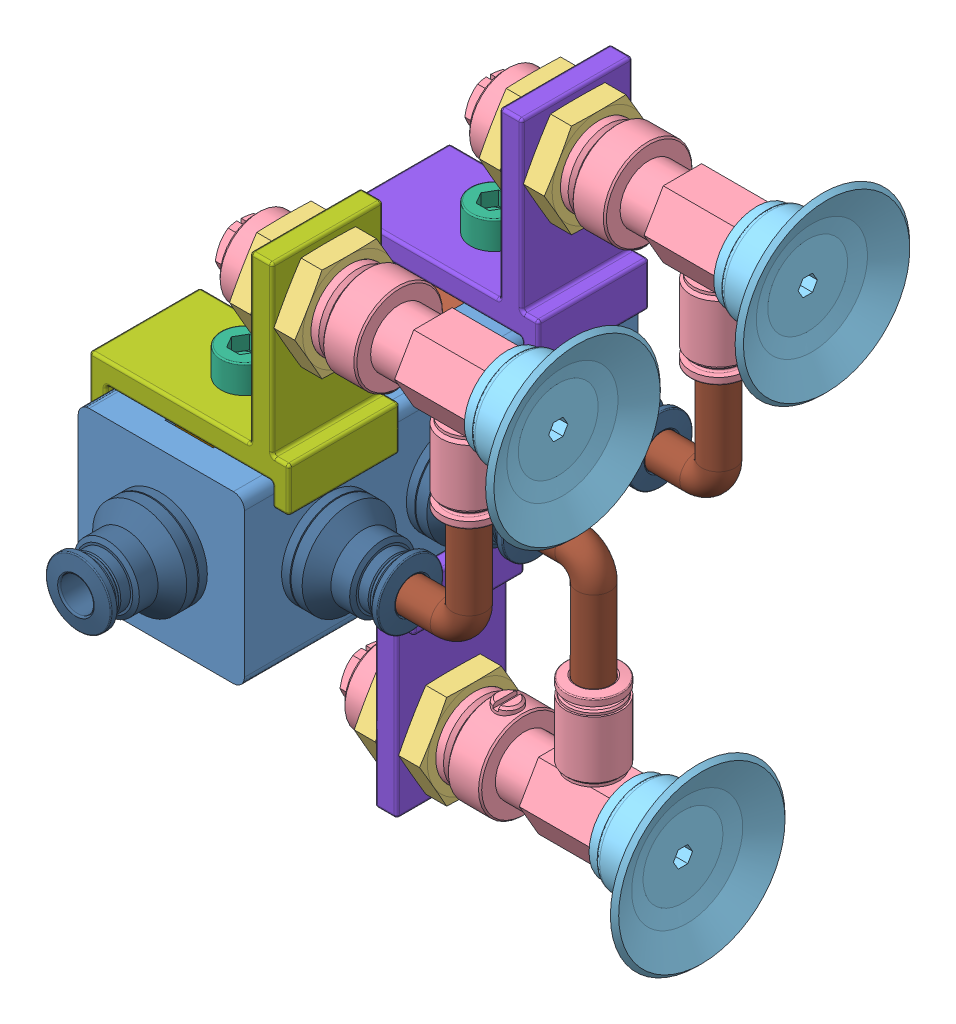
SolidWorks assembly assieme_ventose, configuration Default. Lengths in mm.
Overall size (78 109.5 91.15).
30 component instances, 11 part files, 54 mates.
Components (placement in the parent):
- aluminiumm 30x30 670mm-1: aluminiumm 30x30 670mm [Default] at (-0.0409 0.674 335) size (30 30 71)
- ecrou profil-1: ecrou profil [Default] at (-0.0409 9.834 352.85) x (-1 0 0) z (0 -1 0) size (15.9 15.7 7.3)
- 189174_ESG-30-SF-HD-QS.stp-1: 189174_ESG-30-SF-HD-QS.stp [Default] at (48.9591 39.674 390) x (0 -1 0) z (0 0 -1) size (36.15 61.01 31.5)
  - 130519 ESHM-M14x1.stp-1: 130519 ESHM-M14x1.stp [Default] at (0 38 0) size (19.64 4.01 19.64)
  - 130519 ESHM-M14x1.stp-2: 130519 ESHM-M14x1.stp [Default] at (0 30 0) size (19.64 4.01 19.64)
  - 189239 ESH-HD-4-QS_part---(0).stp-1: 189239 ESH-HD-4-QS_part---(0).stp [Default] at origin size (28.4 50.01 16)
  - 189302 ESS-30-SF.stp-1: 189302 ESS-30-SF.stp [Default] at (0 -11 0) size (31.5 16 31.5)
- socket head cap screw_iso-3: socket head cap screw_iso [ISO 4762 M5 x 12 - 12N] at (-0.0409 24.674 345) x (0 -1 0) z (-0.866025 0 0.5) size (17 8.5 8.5)
- socket head cap screw_iso-4: socket head cap screw_iso [ISO 4762 M5 x 12 - 12N] at (-0.0409 24.674 390) x (0 -1 0) z (-0.866025 0 -0.5) size (17 8.5 8.5)
- 189174_ESG-30-SF-HD-QS.stp-2: 189174_ESG-30-SF-HD-QS.stp [Default] at (48.9591 -38.326 367.5) x (0 1 0) z (0 0 1) size (36.15 61.01 31.5)
  - 130519 ESHM-M14x1.stp-1: 130519 ESHM-M14x1.stp [Default] at (0 38 0) size (19.64 4.01 19.64)
  - 130519 ESHM-M14x1.stp-2: 130519 ESHM-M14x1.stp [Default] at (0 30 0) size (19.64 4.01 19.64)
  - 189239 ESH-HD-4-QS_part---(0).stp-1: 189239 ESH-HD-4-QS_part---(0).stp [Default] at origin size (28.4 50.01 16)
  - 189302 ESS-30-SF.stp-1: 189302 ESS-30-SF.stp [Default] at (0 -11 0) size (31.5 16 31.5)
- Parte12-1: Parte12 [Default] at (14.9591 39.674 390) x (0 -1 0) z (-1 0 0) size (38 20 36)
- 189174_ESG-30-SF-HD-QS.stp-4: 189174_ESG-30-SF-HD-QS.stp [Default] at (48.9591 39.674 345) x (0 -1 0) z (0 0 -1) size (36.15 61.01 31.5)
  - 130519 ESHM-M14x1.stp-1: 130519 ESHM-M14x1.stp [Default] at (0 38 0) size (19.64 4.01 19.64)
  - 130519 ESHM-M14x1.stp-2: 130519 ESHM-M14x1.stp [Default] at (0 30 0) size (19.64 4.01 19.64)
  - 189239 ESH-HD-4-QS_part---(0).stp-1: 189239 ESH-HD-4-QS_part---(0).stp [Default] at origin size (28.4 50.01 16)
  - 189302 ESS-30-SF.stp-1: 189302 ESS-30-SF.stp [Default] at (0 -11 0) size (31.5 16 31.5)
- Parte12_-1: Parte12_ [Default] at (14.9591 39.674 345) x (0 -1 0) z (-1 0 0) size (38 20 36)
- Parte12_-2: Parte12_ [Default] at (14.9591 -38.326 367.5) x (0 1 0) z (-1 0 0) size (38 20 36)
- ecrou profil_-1: ecrou profil_ [Default] at (-0.0409 9.834 382.15) x (1 0 0) z (0 -1 0) size (15.9 15.7 7.3)
- ecrou profil_-2: ecrou profil_ [Default] at (-0.0409 -8.486 375.35) x (1 0 0) z (0 1 0) size (15.9 15.7 7.3)
- socket head cap screw_iso-7: socket head cap screw_iso [ISO 4762 M5 x 12 - 12N] at (-0.0409 -23.326 367.5) x (0 1 0) z (0 0 -1) size (17 8.5 8.5)
- 186108_QS-G1_4-6-I.stp-4: 186108_QS-G1_4-6-I.stp [Default] at (14.9591 0.6232 390) x (0 0 1) z (-1 0 0) size (17 17 20.2)
- 186108_QS-G1_4-6-I.stp-5: 186108_QS-G1_4-6-I.stp [Default] at (14.9591 0.6232 367.5) x (0 0 1) z (-1 0 0) size (17 17 20.2)
- 186108_QS-G1_4-6-I.stp-6: 186108_QS-G1_4-6-I.stp [Default] at (14.9591 0.6232 345) x (0 0 1) z (-1 0 0) size (17 17 20.2)
- tubi_racc-1: tubi_racc [Default] at (14.9591 0.674 335) x (0 0 -1) z (1 0 0) size (51 64 28.5)
- 186108_QS-G1_4-6-I.stp-7: 186108_QS-G1_4-6-I.stp [Default] at (-0.0409 0.674 405) x (-0.923728 -0.383049 0) z (0 0 -1) size (17 17 20.2)
Mates (geometry in assembly coordinates):
- Coincidente321: coincident anti-aligned: plane of aluminiumm 30x30 670mm-1 through (-15.0409 15.674 400) normal (0 1 0); plane of Parte12-1 through (-15.0409 15.674 380) normal (0 -1 0)
- Coincidente331: coincident anti-aligned: plane of aluminiumm 30x30 670mm-1 through (14.9591 5.024 400) normal (1 0 0); plane of Parte12-1 through (14.9591 39.674 390) normal (-1 0 0)
- Coincidente341: coincident anti-aligned: plane of aluminiumm 30x30 670mm-1 through (12.9591 13.674 400) normal (0 0 -1); plane of Parte12-1 through (10.9591 49.674 400) normal (0 0 1)
- Concentrico101: concentric aligned: cylinder of 189174_ESG-30-SF-HD-QS.stp-1/189239 ESH-HD-4-QS_part---(0).stp-1 through (27.9591 39.674 390) axis (1 0 0) radius 7; cylinder of Parte12-1 through (10.9591 39.674 390) axis (1 0 0) radius 7
- Coincidente351: coincident anti-aligned: plane of 189174_ESG-30-SF-HD-QS.stp-1/130519 ESHM-M14x1.stp-2 through (14.9591 39.674 390) normal (-1 0 0); plane of Parte12-1 through (14.9591 39.674 390) normal (1 0 0)
- Coincidente371: coincident anti-aligned: plane of aluminiumm 30x30 670mm-1 through (-15.0409 15.674 400) normal (0 1 0); plane of Parte13-1 through (14.9591 15.674 632.2378) normal (0 -1 0)
- Coincidente381: coincident anti-aligned: plane of aluminiumm 30x30 670mm-1 through (-15.0409 -14.326 400) normal (-1 0 0); plane of Parte13-1 through (-15.0409 15.674 632.2378) normal (1 0 0)
- Concentrico111: concentric anti-aligned: cylinder of 189174_ESG-30-SF-HD-QS.stp-3/189239 ESH-HD-4-QS_part---(0).stp-1 through (56.9591 0.674 910.1448) axis (1 0 0) radius 7; cylinder of Parte13-1 through (59.9591 0.674 622.2378) axis (-1 0 0) radius 7
- Coincidente391: coincident anti-aligned: plane of 189174_ESG-30-SF-HD-QS.stp-3/130519 ESHM-M14x1.stp-1 through (39.9591 9.174 910.1448) normal (1 0 0); plane of Parte13-1 through (39.9591 -14.326 632.2378) normal (-1 0 0)
- Parallelo121: parallel anti-aligned: plane of 189174_ESG-30-SF-HD-QS.stp-3/130519 ESHM-M14x1.stp-1 through (31.9591 9.174 915.0523) normal (0 1 0); plane of Parte13-1 through (39.9591 15.674 632.2378) normal (0 -1 0)
- Concentrico112: concentric anti-aligned: cylinder of Parte13-1 through (59.9591 0.674 622.2378) axis (-1 0 0) radius 7; cylinder of 189174_ESG-30-SF-HD-QS.stp-4/189239 ESH-HD-4-QS_part---(0).stp-1 through (27.9591 39.674 345) axis (1 0 0) radius 7
- Coincidente392: coincident anti-aligned: plane of Parte13-1 through (39.9591 -14.326 632.2378) normal (-1 0 0); plane of 189174_ESG-30-SF-HD-QS.stp-4/130519 ESHM-M14x1.stp-1 through (10.9591 31.174 345) normal (1 0 0)
- Parallelo122: parallel aligned: plane of Parte13-1 through (39.9591 15.674 632.2378) normal (0 -1 0); plane of 189174_ESG-30-SF-HD-QS.stp-4/130519 ESHM-M14x1.stp-1 through (2.9591 48.174 349.9075) normal (0 1 0)
- Coincidente393: coincident anti-aligned: plane of aluminiumm 30x30 670mm-1 through (-15.0409 15.674 400) normal (0 1 0); plane of Parte12_-1 through (-15.0409 15.674 335) normal (0 -1 0)
- Coincidente394: coincident anti-aligned: plane of aluminiumm 30x30 670mm-1 through (-15.0409 -14.326 400) normal (-1 0 0); plane of Parte12_-1 through (-15.0409 39.674 345) normal (1 0 0)
- Concentrico113: concentric aligned: cylinder of 189174_ESG-30-SF-HD-QS.stp-4/189239 ESH-HD-4-QS_part---(0).stp-1 through (27.9591 39.674 345) axis (1 0 0) radius 7; cylinder of Parte12_-1 through (10.9591 39.674 345) axis (1 0 0) radius 7
- Coincidente395: coincident anti-aligned: plane of 189174_ESG-30-SF-HD-QS.stp-4/130519 ESHM-M14x1.stp-2 through (14.9591 39.674 345) normal (-1 0 0); plane of Parte12_-1 through (14.9591 39.674 345) normal (1 0 0)
- Coincidente397: coincident anti-aligned: plane of aluminiumm 30x30 670mm-1 through (4.3091 -14.326 400) normal (0 -1 0); plane of Parte12_-2 through (-15.0409 -14.326 377.5) normal (0 1 0)
- Coincidente398: coincident anti-aligned: plane of aluminiumm 30x30 670mm-1 through (14.9591 5.024 400) normal (1 0 0); plane of Parte12_-2 through (14.9591 -38.326 367.5) normal (-1 0 0)
- Concentrico114: concentric aligned: cylinder of 189174_ESG-30-SF-HD-QS.stp-2/189239 ESH-HD-4-QS_part---(0).stp-1 through (27.9591 -38.326 367.5) axis (1 0 0) radius 7; cylinder of Parte12_-2 through (10.9591 -38.326 367.5) axis (1 0 0) radius 7
- Coincidente399: coincident anti-aligned: plane of 189174_ESG-30-SF-HD-QS.stp-2/130519 ESHM-M14x1.stp-2 through (14.9591 -38.326 367.5) normal (-1 0 0); plane of Parte12_-2 through (14.9591 -38.326 367.5) normal (1 0 0)
- Coincidente401: coincident anti-aligned: plane of aluminiumm 30x30 670mm-1 through (12.9591 -12.326 335) normal (0 0 1); plane of Parte12_-1 through (10.9591 49.674 335) normal (0 0 -1)
- Concentrico115: concentric aligned: cylinder of ecrou profil-1 through (-0.0409 23.634 345) axis (0 -1 0) radius 2.5; cylinder of Parte12_-1 through (-0.0409 20.674 345) axis (0 -1 0) radius 2.4622
- Parallelo125: parallel anti-aligned: plane of aluminiumm 30x30 670mm-1 through (-8.5009 10.334 400) normal (1 0 0); plane of ecrou profil-1 through (-7.9909 12.234 337.15) normal (-1 0 0)
- Coincidente403: coincident anti-aligned: plane of aluminiumm 30x30 670mm-1 through (8.4191 13.934 400) normal (0 -1 0); plane of ecrou profil-1 through (7.9091 13.934 337.15) normal (0 1 0)
- Concentrico116: concentric anti-aligned: cylinder of socket head cap screw_iso-3 through (-0.0409 56.424 345) axis (0 1 0) radius 2.5; cylinder of Parte12_-1 through (-0.0409 20.674 345) axis (0 -1 0) radius 2.4622
- Coincidente404: coincident anti-aligned: plane of socket head cap screw_iso-3 through (2.0841 19.674 348.6806) normal (0 -1 0); plane of Parte12_-1 through (-15.0409 19.674 335) normal (0 1 0)
- Concentrico117: concentric aligned: cylinder of Parte12-1 through (-0.0409 20.674 390) axis (0 -1 0) radius 2.4622; cylinder of ecrou profil_-1 through (-0.0409 23.634 390) axis (0 -1 0) radius 2.5
- Coincidente405: coincident anti-aligned: plane of aluminiumm 30x30 670mm-1 through (-8.5009 13.934 400) normal (0 -1 0); plane of ecrou profil_-1 through (-7.9909 13.934 397.85) normal (0 1 0)
- Parallelo126: parallel anti-aligned: plane of aluminiumm 30x30 670mm-1 through (-8.5009 10.334 400) normal (1 0 0); plane of ecrou profil_-1 through (-7.9909 12.234 397.85) normal (-1 0 0)
- Concentrico118: concentric anti-aligned: cylinder of socket head cap screw_iso-4 through (-0.0409 56.424 390) axis (0 1 0) radius 2.5; cylinder of Parte12-1 through (-0.0409 20.674 390) axis (0 -1 0) radius 2.4622
- Coincidente407: coincident anti-aligned: plane of socket head cap screw_iso-4 through (-2.1659 19.674 393.6806) normal (0 -1 0); plane of Parte12-1 through (-15.0409 19.674 380) normal (0 1 0)
- Parallelo127: parallel aligned: plane of socket head cap screw_iso-4 through (-1.2198 22.174 387.958) normal (0 0 1); plane of Parte12-1 through (10.9591 49.674 400) normal (0 0 1)
- Parallelo128: parallel anti-aligned: plane of socket head cap screw_iso-3 through (-1.2198 22.174 342.958) normal (0 0 1); plane of Parte12_-1 through (10.9591 49.674 335) normal (0 0 -1)
- Distanza1: distance = 2.5 mm anti-aligned: plane of Parte12_-2 through (10.9591 -48.326 357.5) normal (0 0 -1); plane of Parte12_-1 through (10.9591 49.674 355) normal (0 0 1)
- Concentrico119: concentric aligned: cylinder of Parte12_-2 through (-0.0409 -19.326 367.5) axis (0 1 0) radius 2.4622; cylinder of ecrou profil_-2 through (-0.0409 -22.286 367.5) axis (0 1 0) radius 2.5
- Parallelo129: parallel anti-aligned: plane of aluminiumm 30x30 670mm-1 through (-8.461 -8.9178 400) normal (1 0 0); plane of ecrou profil_-2 through (-7.9909 -10.886 359.65) normal (-1 0 0)
- Coincidente413: coincident anti-aligned: plane of aluminiumm 30x30 670mm-1 through (-8.461 -12.586 400) normal (0 1 0); plane of ecrou profil_-2 through (-7.9909 -12.586 359.65) normal (0 -1 0)
- Concentrico120: concentric anti-aligned: cylinder of Parte12_-2 through (-0.0409 -19.326 367.5) axis (0 1 0) radius 2.4622; cylinder of socket head cap screw_iso-7 through (-0.0409 -55.076 367.5) axis (0 -1 0) radius 2.5
- Parallelo130: parallel aligned: plane of socket head cap screw_iso-7 through (1.1381 -20.826 369.542) normal (0 0 -1); plane of Parte12_-2 through (10.9591 -48.326 357.5) normal (0 0 -1)
- Coincidente415: coincident anti-aligned: plane of Parte12_-2 through (-15.0409 -18.326 377.5) normal (0 -1 0); plane of socket head cap screw_iso-7 through (4.2091 -18.326 367.5) normal (0 1 0)
- Parallelo131: parallel aligned: plane of 189174_ESG-30-SF-HD-QS.stp-4/189239 ESH-HD-4-QS_part---(0).stp-1 through (33.9591 45.674 341.5359) normal (0 1 0); plane of Parte12_-1 through (10.9591 49.674 355) normal (0 1 0)
- Parallelo132: parallel aligned: plane of 189174_ESG-30-SF-HD-QS.stp-1/189239 ESH-HD-4-QS_part---(0).stp-1 through (33.9591 45.674 386.5359) normal (0 1 0); plane of Parte12-1 through (10.9591 49.674 400) normal (0 1 0)
- Parallelo134: parallel aligned: plane of Parte12_-2 through (10.9591 -48.326 357.5) normal (0 -1 0); plane of 189174_ESG-30-SF-HD-QS.stp-2/189239 ESH-HD-4-QS_part---(0).stp-1 through (33.9591 -44.326 370.9641) normal (0 -1 0)
- Coincidente420: coincident aligned: plane of aluminiumm 30x30 670mm-1 through (-0.0409 0.674 335) normal (0 1 0); plane of Assieme3^Assieme1-1/7849_FR-4-1_4-C.stp-1 through (2.2699 0.674 498.6939) normal (0 1 0)
- Parallelo135: parallel aligned: plane of aluminiumm 30x30 670mm-1 through (-15.0409 -14.326 400) normal (-1 0 0); plane of Assieme3^Assieme1-1/7849_FR-4-1_4-C.stp-1/7849 FR-4-1_4-C - P1.stp-1 through (-12.7301 -13.326 454.1939) normal (-1 0 0)
- Coincidente422: coincident anti-aligned: plane of 189174_ESG-30-SF-HD-QS.stp-1 through (48.9591 39.674 390) normal (0 0 -1); plane of 186108_QS-G1_4-6-I.stp-4 through (14.9591 0.6232 390) normal (0 0 1)
- SulPosto1: in place: plane of aluminiumm 30x30 670mm-1 through (14.9591 5.024 400) normal (1 0 0); plane of ? through (14.9591 0 0) normal (1 0 0); moOrthogonalPlaneRef_w of aluminiumm 30x30 670mm-1 through (14.9591 5.024 400) normal (1 0 0); plane of ? through (14.9591 0 0) normal (0 1 0); plane of aluminiumm 30x30 670mm-1 through (14.9591 5.024 400) normal (1 0 0); plane of ? through (14.9591 0 0) normal (0 0 -1); plane of aluminiumm 30x30 670mm-1 through (14.9591 5.024 400) normal (1 0 0); unknown of tubi_racc-1
- Coincidente423: coincident aligned: plane of aluminiumm 30x30 670mm-1; plane of tubi_racc-1
- Coincidente424: coincident aligned: moOrthogonalPlaneRef_w of aluminiumm 30x30 670mm-1 through (14.9591 0.674 335) normal (0 1 0); plane of tubi_racc-1 through (14.9591 0.674 335) normal (0 1 0)
- Coincidente425: coincident anti-aligned: moOrthogonalPlaneRef_w of aluminiumm 30x30 670mm-1 through (14.9591 0.674 335) normal (0 0 1); plane of tubi_racc-1 through (14.9591 0.674 335) normal (0 0 -1)
- Coincidente426: coincident anti-aligned: plane of aluminiumm 30x30 670mm-1 through (12.9591 13.674 405) normal (0 0 1); plane of 186350_QS-G1_4-12.stp-2 through (1.4857 13.4536 401) normal (0 0 -1)
- Coincidente427: coincident anti-aligned: plane of aluminiumm 30x30 670mm-1 through (12.9591 13.674 405) normal (0 0 1); plane of 186108_QS-G1_4-6-I.stp-7 through (-2.5607 6.7508 405) normal (0 0 -1)
- Concentrico122: concentric anti-aligned: cylinder of aluminiumm 30x30 670mm-1 through (-0.0409 0.674 400) axis (0 0 -1) radius 3; cylinder of 186108_QS-G1_4-6-I.stp-7 through (-0.0409 0.674 420.4) axis (0 0 1) radius 3
